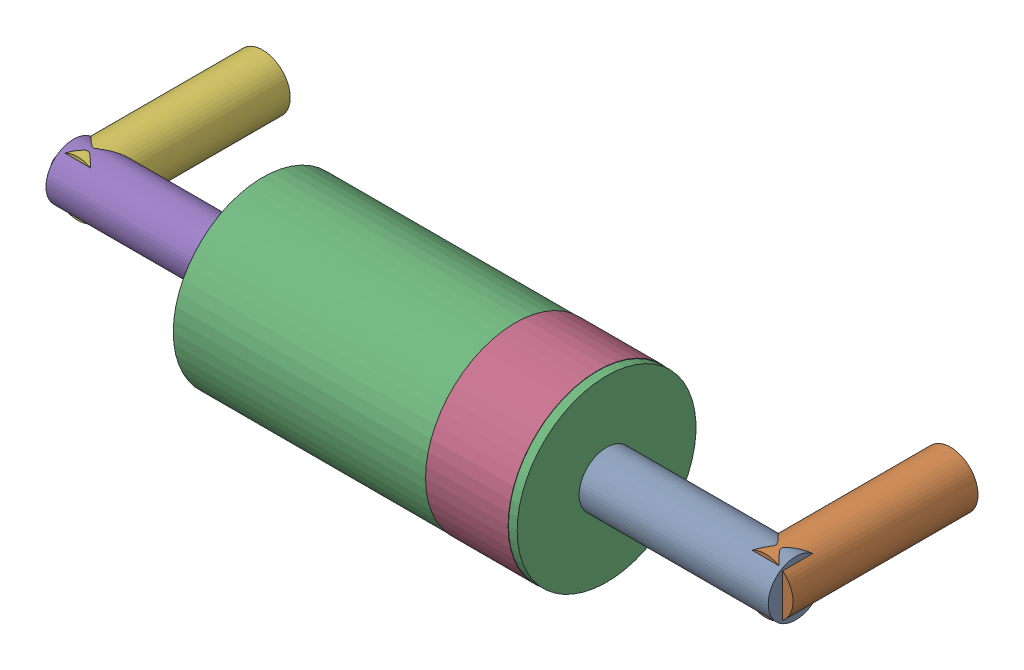
SolidWorks assembly D3, configuration Default. Lengths in mm.
Overall size (10.8 2.61 3.81).
12 component instances, 6 part files, 0 mates.
Components (placement in the parent):
- -1733042672-1: -1733042672 [Default] at (514.2502 272.9977 1.5) x (0 0 -1) z (-1 0 0) size (0.8 0.8 2.75)
  - Cylinder-1: Cylinder [Default] at origin size (0.8 0.8 2.75)
- -1733042992-1: -1733042992 [Default] at (513.9999 272.9999 -1) x (-1 0 0) z (0 0 1) size (0.8 0.8 2.69)
  - Cylinder_2-1: Cylinder_2 [Default] at origin size (0.8 0.8 2.69)
- -1733042432-1: -1733042432 [Default] at (511.5001 272.9975 1.5) x (0 0 -1) z (-1 0 0) size (2.6 2.6 5)
  - Cylinder_3-1: Cylinder_3 [Default] at origin size (2.6 2.6 5)
- -1733042152-1: -1733042152 [Default] at (511.3731 272.9976 1.5) x (0 0 -1) z (-1 0 0) size (2.61 2.61 1.2)
  - Cylinder_4-1: Cylinder_4 [Default] at origin size (2.61 2.61 1.2)
- -1733041072-1: -1733041072 [Default] at (503.7497 273.0023 1.5) x (0 0 -1) z (1 0 0) size (0.8 0.8 2.75)
  - Cylinder_5-1: Cylinder_5 [Default] at origin size (0.8 0.8 2.75)
- -1733041192-1: -1733041192 [Default] at (504.0001 273.0001 -1) x (1 0 0) z (0 0 1) size (0.8 0.8 2.69)
  - Cylinder_6-1: Cylinder_6 [Default] at origin size (0.8 0.8 2.69)
